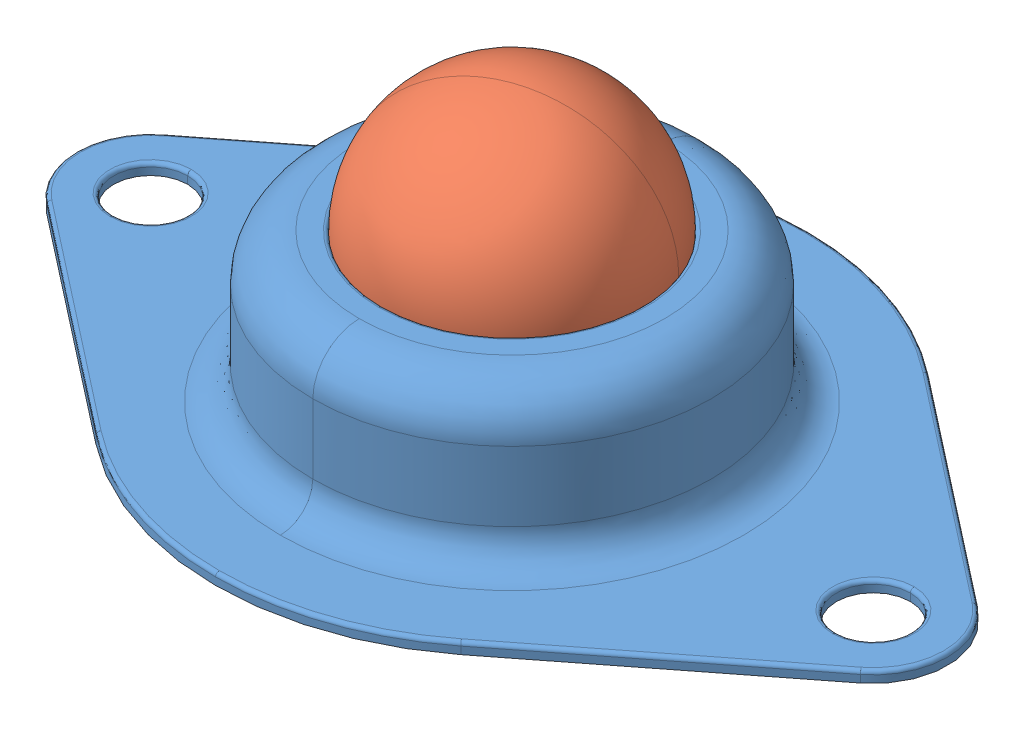
SolidWorks assembly Caster Ball Wheel.STEP, configuration Default. Lengths in mm.
Overall size (47 18.41 32).
2 component instances, 2 part files, 0 mates.
Components (placement in the parent):
- Wheel''s Body.STEP-1: Wheel''s Body.STEP [Default] at origin size (47 8.6 32)
- Ball.STEP-1: Ball.STEP [Default] at (0 8.6 0) x (0.870425 -0.365315 -0.330008) z (0.347375 -0.019238 0.937529) size (14 14 14)
